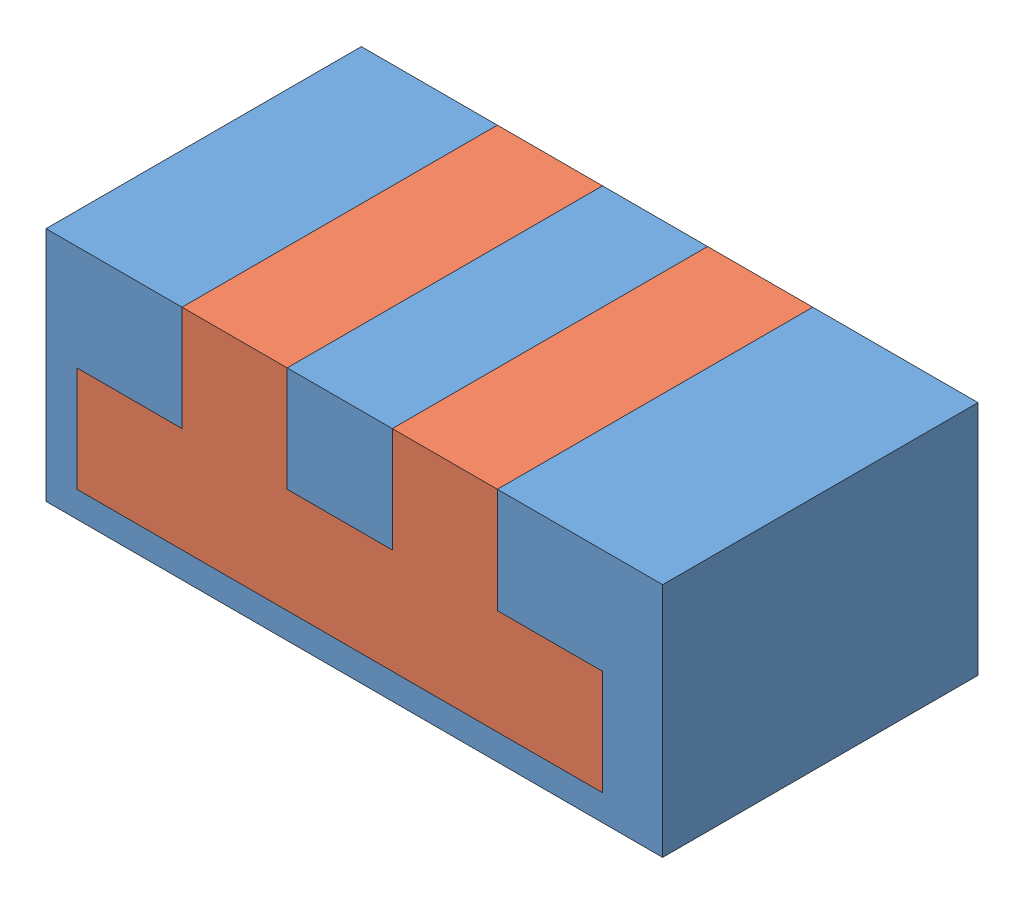
SolidWorks assembly Assem1, configuration Default. Lengths in mm.
Overall size (58.66 22.47 30).
2 component instances, 2 part files, 3 mates.
Components (placement in the parent):
- outer-1: outer [Default] at (-11.5507 1.1875 5.2884) size (58.66 22.47 30)
- inner-1: inner [Default] at (-11.5507 1.1875 5.2884) size (50 20 30)
Mates (geometry in assembly coordinates):
- Coincident1: coincident: plane of outer-1 through (28.4493 11.1875 35.2884) normal (-1 0 0); plane of inner-1 through (28.4493 11.1875 35.2884) normal (1 0 0)
- Coincident3: coincident: plane of outer-1 through (-11.5507 1.1875 35.2884) normal (0 0 1); plane of inner-1 through (-11.5507 1.1875 35.2884) normal (0 0 1)
- Coincident4: coincident aligned: plane of outer-1 through (-14.4939 21.1875 35.2884) normal (0 1 0); plane of inner-1 through (8.4493 21.1875 35.2884) normal (0 1 0)
